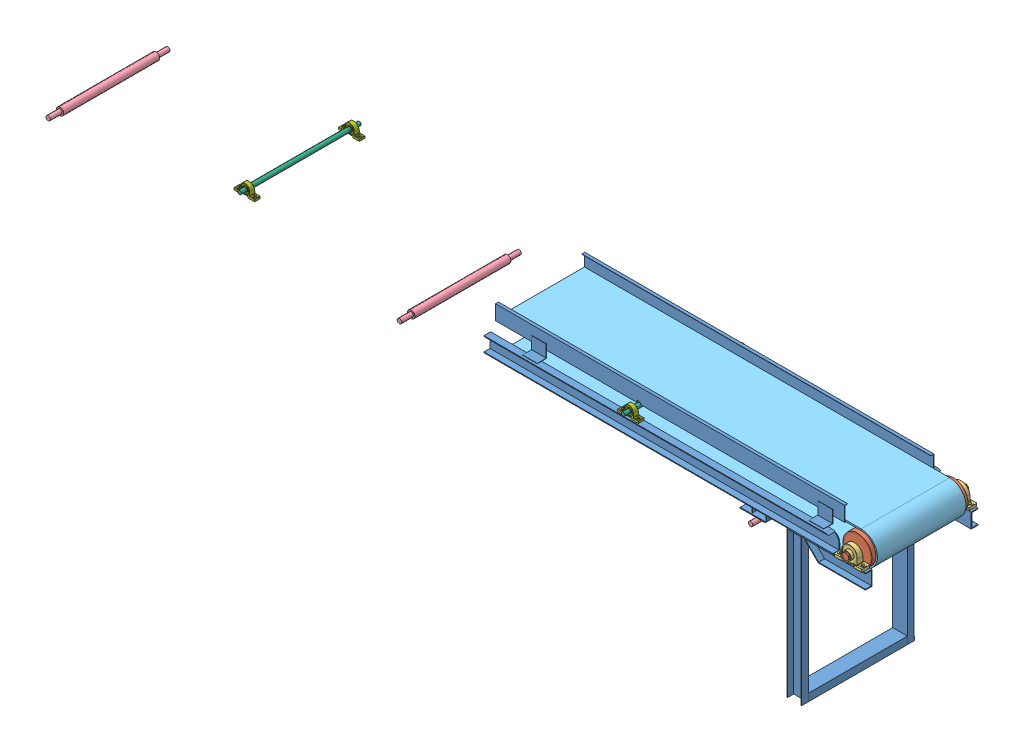
SolidWorks assembly nastrodx, configuration Default. Lengths in mm.
Overall size (2586.13 1242.59 812.17).
18 component instances, 10 part files, 36 mates.
Components (placement in the parent):
- C-channel -b-up-2: C-channel -b-up [Default<As Machined>] at (4036.4781 3775.6231 338.4141) x (0.000207 -1 -0.000382) z (-1 -0.000206 -0.000489) size (1248 1076.8 6547.03)
- roller-belt-Motor-up-1: roller-belt-Motor-up [Default] at (7146.6561 3780.3929 4.9357) x (0.000489 0.000382 -1) z (1 0 0.000489) size (812 200 200)
- Uct 209-up-1: Uct 209-up [Default] at (956.4633 3774.9756 367.9088) x (1 0.000206 0.000489) z (-0.000489 -0.000382 1) size (144 117 54.7)
- Extender-screw-up-1: Extender-screw-up [Default] at (892.9633 3774.9625 367.8777) x (0.000489 0 -1) z (-1 -0.000206 -0.000489) size (46.02 42.15 250)
- Bearing-b_P209_45-up-1: Bearing-b_P209_45-up [Default] at (7146.4904 3726.2546 366.915) x (1 0.000206 0.000489) z (-0.000489 -0.000382 1) size (190 108 62)
- upper-roller-inside-up-1: upper-roller-inside-up [Default] at (6502.8061 3649.373 4.571) x (1 0 0.000489) z (-0.000489 -0.000382 1) size (50 50 810)
- Bearing-b_P209_45-up-2: Bearing-b_P209_45-up [Default] at (7146.8442 3726.5311 -357.0849) x (-1 -0.000206 -0.000489) z (0.000489 0.000382 -1) size (190 108 62)
- Uct 209-up-2: Uct 209-up [Default] at (956.821 3775.2551 -364.0911) x (1 0.000206 0.000489) z (0.000489 0.000382 -1) size (144 117 54.7)
- Extender-screw-up-2: Extender-screw-up [Default] at (893.321 3775.242 -364.1221) x (0.000489 0.000764 -1) z (-1 -0.000206 -0.000489) size (46.02 42.15 250)
- upper-roller-inside-up-2: upper-roller-inside-up [Default] at (4122.8064 3648.8818 3.4078) x (1 0 0.000489) z (-0.000489 -0.000382 1) size (50 50 810)
- upper-roller-inside-up-3: upper-roller-inside-up [Default] at (1742.8067 3648.3906 2.2446) x (1 0 0.000489) z (-0.000489 -0.000382 1) size (50 50 810)
- Belt^nastrodx-1: Belt [Default] at (4036.6418 3775.751 3.4142) x (-0.000207 1 0.000382) z (0.000489 0.000382 -1) size (224 6410.02 600) (virtual)
- roller-upper-2: roller-upper [Default] at (5639.6653 3862.5818 4.2307) x (1 0 0.000489) z (-0.000489 -0.000382 1) size (29 29 810)
- UCP-205-1: UCP-205 [Default] at (5639.4923 3862.4467 358.2306) x (0.000489 0.000382 -1) z (1 0 0.000489) size (38.7 70 140)
- UCP-205-2: UCP-205 [Default] at (5639.8383 3862.717 -349.7693) x (0.000489 0.000382 -1) z (1 0.000206 0.000489) size (38.7 70 140)
- UCP-205-3: UCP-205 [Default] at (3039.8387 3862.1804 -351.04) x (0.000489 0.000382 -1) z (1 0.000206 0.000489) size (38.7 70 140)
- UCP-205-4: UCP-205 [Default] at (3039.4927 3861.9101 356.9599) x (0.000489 0.000382 -1) z (1 0 0.000489) size (38.7 70 140)
- roller-upper-3: roller-upper [Default] at (3039.6657 3862.0453 2.9599) x (1 0 0.000489) z (-0.000489 -0.000382 1) size (29 29 810)
Mates (geometry in assembly coordinates):
- Coincident1: coincident: plane of C-channel -b-up-2 through (4036.6418 3775.751 3.4142) normal (0.000489 0.000382 -1)
- Concentric1: concentric anti-aligned: cylinder of C-channel -b-up-2 through (956.8005 3775.2391 -322.0911) axis (0.000489 0.000382 -1) radius 25; cylinder of roller-belt-Motor-up -lower-1 through (956.8425 3775.2719 -408.0911) axis (-0.000489 -0.000382 1) radius 22.5
- Width1: width anti-aligned: plane of C-channel -b-up-2 through (1036.7956 3825.2598 -333.0329) normal (-0.000489 -0.000382 1); plane of C-channel -b-up-2 through (1036.4681 3825.004 336.967) normal (0.000489 0.000382 -1); plane of roller-belt-Motor-up -lower-1 through (956.801 3775.2395 -323.0911) normal (0.000489 0.000382 -1); plane of roller-belt-Motor-up -lower-1 through (956.4834 3774.9913 326.9088) normal (-0.000489 -0.000382 1)
- Concentric2: concentric anti-aligned: cylinder of roller-belt-Motor-up -lower-1 through (956.8425 3775.2719 -408.0911) axis (-0.000489 -0.000382 1) radius 22.5; cylinder of Uct 209-up-1 through (956.4486 3774.9641 398.1088) axis (0.000489 0.000382 -1) radius 22.5
- Coincident2: coincident anti-aligned: plane of C-channel -b-up-2 through (810.446 3839.9425 375.8622) normal (-0.000489 -0.000382 1); plane of Uct 209-up-1 through (1005.9473 3833.4828 375.9553) normal (0.000489 0.000382 -1)
- Parallel1: parallel anti-aligned: plane of C-channel -b-up-2 through (810.4487 3826.9425 375.8573) normal (0.000207 -1 -0.000382); plane of Uct 209-up-1 through (1005.9567 3825.9889 359.9524) normal (-0.000207 1 0.000382)
- Concentric3: concentric aligned: cylinder of Uct 209-up-1 through (869.4634 3774.9577 367.8663) axis (1 0.000206 0.000489) radius 14.5; cylinder of Extender-screw-up-1 through (652.4634 3774.9129 367.7602) axis (1 0.000206 0.000489) radius 14.5
- Coincident3: coincident anti-aligned: plane of Uct 209-up-1 through (885.4696 3793.2991 347.3811) normal (1 0.000206 0.000489); plane of Extender-screw-up-1 through (885.4633 3774.961 367.8741) normal (-1 -0.000206 -0.000489)
- Coincident4: coincident anti-aligned: plane of C-channel -b-up-2 through (6936.5192 3726.2216 339.8124) normal (-0.000207 1 0.000382); plane of Bearing-b_P209_45-up-1 through (7051.4772 3726.2247 393.8686) normal (0.000207 -1 -0.000382)
- Coincident5: coincident aligned: plane of C-channel -b-up-2 through (4036.4781 3775.6231 338.4141) normal (0.000489 0.000382 -1); plane of Bearing-b_P209_45-up-1 through (7146.5036 3726.265 339.915) normal (0.000489 0.000382 -1)
- Concentric4: concentric aligned: cylinder of Bearing-b_P209_45-up-1 through (7146.5193 3780.286 284.9356) axis (-0.000489 -0.000382 1) radius 22.5; cylinder of roller-belt-Motor-up-1 through (7146.8545 3780.5479 -401.0642) axis (-0.000489 -0.000382 1) radius 22.5
- Coincident6: coincident anti-aligned: plane of C-channel -b-up-2 through (-723.5039 3690.6538 336.0556) normal (0.000207 -1 -0.000382); plane of UCP206-3 through (1710.6085 3691.1361 389.7453) normal (-0.000207 1 0.000382)
- Width4: width aligned: plane of C-channel -b-up-2 through (1657.6337 3691.1448 338.2194) normal (-1 -0.000206 -0.000489); plane of C-channel -b-up-2 through (1827.6337 3691.1799 338.3025) normal (1 0.000206 0.000489); plane of UCP206-3 through (1660.11 3691.1268 386.7206) normal (-1 -0.000206 -0.000489); plane of UCP206-3 through (1825.1305 3691.1769 344.8013) normal (1 0.000206 0.000489)
- Width5: width anti-aligned: plane of UCP206-3 through (1777.632 3691.1682 341.7781) normal (0.000489 0.000382 -1); plane of UCP206-3 through (1822.1085 3691.1591 389.7998) normal (-0.000489 -0.000382 1); plane of C-channel -b-up-2 through (1827.6068 3691.1589 393.3025) normal (-0.000489 -0.000382 1); plane of C-channel -b-up-2 through (1827.6337 3691.1799 338.3025) normal (0.000489 0.000382 -1)
- Coincident8: coincident anti-aligned: plane of C-channel -b-up-2 through (1656.4957 3691.145 337.2188) normal (0.000207 -1 -0.000382); plane of UCP206-1 through (4090.6082 3691.6273 390.9085) normal (-0.000207 1 0.000382)
- Width6: width anti-aligned: plane of UCP206-1 through (4040.1097 3691.618 387.8838) normal (-1 -0.000206 -0.000489); plane of UCP206-1 through (4205.1302 3691.6681 345.9645) normal (1 0.000206 0.000489); plane of C-channel -b-up-2 through (4207.6333 3691.6711 339.4657) normal (1 0.000206 0.000489); plane of C-channel -b-up-2 through (4037.6334 3691.636 339.3826) normal (-1 -0.000206 -0.000489)
- Width7: width anti-aligned: plane of UCP206-1 through (4087.6082 3691.6266 390.907) normal (-0.000489 -0.000382 1); plane of UCP206-1 through (4043.1316 3691.6358 342.8853) normal (0.000489 0.000382 -1); plane of C-channel -b-up-2 through (4207.6333 3691.6711 339.4657) normal (0.000489 0.000382 -1); plane of C-channel -b-up-2 through (4207.6065 3691.6501 394.4657) normal (-0.000489 -0.000382 1)
- Coincident9: coincident anti-aligned: plane of C-channel -b-up-2 through (4036.4954 3691.6361 338.3821) normal (0.000207 -1 -0.000382); plane of UCP206-2 through (6470.6078 3692.1184 392.0717) normal (-0.000207 1 0.000382)
- Width8: width anti-aligned: plane of C-channel -b-up-2 through (6587.6061 3692.1412 395.6289) normal (-0.000489 -0.000382 1); plane of C-channel -b-up-2 through (6587.633 3692.1622 340.6289) normal (0.000489 0.000382 -1); plane of UCP206-2 through (6423.1313 3692.127 344.0485) normal (0.000489 0.000382 -1); plane of UCP206-2 through (6467.6078 3692.1178 392.0702) normal (-0.000489 -0.000382 1)
- Width9: width anti-aligned: plane of C-channel -b-up-2 through (6417.633 3692.1272 340.5458) normal (-1 -0.000206 -0.000489); plane of C-channel -b-up-2 through (6587.633 3692.1622 340.6289) normal (1 0.000206 0.000489); plane of UCP206-2 through (6585.1298 3692.1592 347.1277) normal (1 0.000206 0.000489); plane of UCP206-2 through (6420.1093 3692.1092 389.047) normal (-1 -0.000206 -0.000489)
- Concentric5: concentric anti-aligned: cylinder of upper-roller-inside-up-1 through (6502.6082 3649.2184 409.571) axis (0.000489 0.000382 -1) radius 15; cylinder of UCP206-2 through (6502.6358 3649.24 352.933) axis (-0.000489 -0.000382 1) radius 15
- Concentric6: concentric anti-aligned: cylinder of UCP206-1 through (4122.6362 3648.7488 351.7698) axis (-0.000489 -0.000382 1) radius 15; cylinder of upper-roller-inside-up-2 through (4122.6085 3648.7272 408.4078) axis (0.000489 0.000382 -1) radius 15
- Concentric7: concentric anti-aligned: cylinder of UCP206-3 through (1742.6365 3648.2576 350.6066) axis (-0.000489 -0.000382 1) radius 15; cylinder of upper-roller-inside-up-3 through (1742.6088 3648.236 407.2446) axis (0.000489 0.000382 -1) radius 15
- Width12: width anti-aligned: plane of upper-roller-inside-up-3 through (1742.6088 3648.236 407.2446) normal (-0.000489 -0.000382 1); plane of upper-roller-inside-up-3 through (1743.0046 3648.5453 -402.7553) normal (0.000489 0.000382 -1); plane of C-channel -b-up-2 through (1036.4681 3825.004 336.967) normal (0.000489 0.000382 -1); plane of C-channel -b-up-2 through (1036.7956 3825.2598 -333.0329) normal (-0.000489 -0.000382 1)
- InPlace1: in place: plane of ? through (4036.6525 3723.6228 3.3943) normal (0.000489 0.000382 -1); plane of ? through (4036.6525 3723.6228 3.3943) normal (0.000489 0.000382 -1); moOrthogonalPlaneRef_w of ? through (4036.6525 3723.6228 3.3943) normal (0.000489 0.000382 -1); plane of ? through (4036.6525 3723.6228 3.3943) normal (1 0.000206 0.000489); plane of ? through (4036.6525 3723.6228 3.3943) normal (0.000489 0.000382 -1); plane of ? through (4036.6525 3723.6228 3.3943) normal (-0.000207 1 0.000382); plane of C-channel -b-up-2 through (4036.6418 3775.751 3.4142) normal (0.000489 0.000382 -1); unknown of Belt^nastrodx-1
- Coincident13: coincident aligned: plane of C-channel -b-up-2; plane of Belt^nastrodx-1
- Coincident14: coincident aligned: moOrthogonalPlaneRef_w of C-channel -b-up-2; plane of Belt^Assembly of conveyor-1 through (4036.6418 3775.751 3.4142) normal (1 0.000206 0.000489)
- Coincident15: coincident anti-aligned: moOrthogonalPlaneRef_w of C-channel -b-up-2; plane of Belt^Assembly of conveyor-1 through (4036.6418 3775.751 3.4142) normal (-0.000207 1 0.000382)
- Concentric11: concentric anti-aligned: cylinder of roller-upper-2 through (5639.4674 3862.4272 409.2306) axis (0.000489 0.000382 -1) radius 12.5; cylinder of UCP-205-1 through (5639.4853 3862.4412 372.5306) axis (-0.000489 -0.000382 1) radius 12.5
- Coincident24: coincident aligned: plane of C-channel -b-up-2 through (1036.4681 3825.004 336.967) normal (0.000489 0.000382 -1); plane of UCP-205-1 through (5571.1016 3838.7539 339.1881) normal (0.000489 0.000382 -1)
- Concentric12: concentric aligned: cylinder of roller-upper-2 through (5639.8632 3862.7365 -400.7693) axis (-0.000489 -0.000382 1) radius 12.5; cylinder of UCP-205-2 through (5639.8313 3862.7115 -335.4693) axis (-0.000489 -0.000382 1) radius 12.5
- Coincident25: coincident anti-aligned: plane of C-channel -b-up-2 through (1036.7956 3825.2598 -333.0329) normal (-0.000207 1 0.000382); plane of UCP-205-2 through (5709.8551 3826.2387 -368.749) normal (0.000207 -1 -0.000382)
- Coincident26: coincident aligned: plane of C-channel -b-up-2 through (1036.7956 3825.2598 -333.0329) normal (-0.000489 -0.000382 1); plane of UCP-205-2 through (5571.4339 3838.9956 -330.8117) normal (-0.000489 -0.000382 1)
- Coincident28: coincident anti-aligned: plane of roller-belt-Motor-up -lower-1 through (956.8425 3775.2719 -408.0911) normal (0.000489 0.000382 -1); plane of Gear_motor-b-up-1 through (972.9459 3759.1753 -408.0893) normal (-0.000489 -0.000382 1)
- Concentric14: concentric anti-aligned: circle of roller-belt-Motor-up -lower-1; cylinder of Gear_motor-b-up-1 through (956.8767 3775.2987 -478.0911) axis (-0.000489 -0.000382 1) radius 17.5
- Parallel2: parallel aligned: plane of C-channel -b-up-2 through (1036.8162 3725.2598 -333.0711) normal (0.000207 -1 -0.000382); plane of Gear_motor-b-up-1 through (1248.8044 3664.8321 -669.7906) normal (0.000207 -1 -0.000382)
